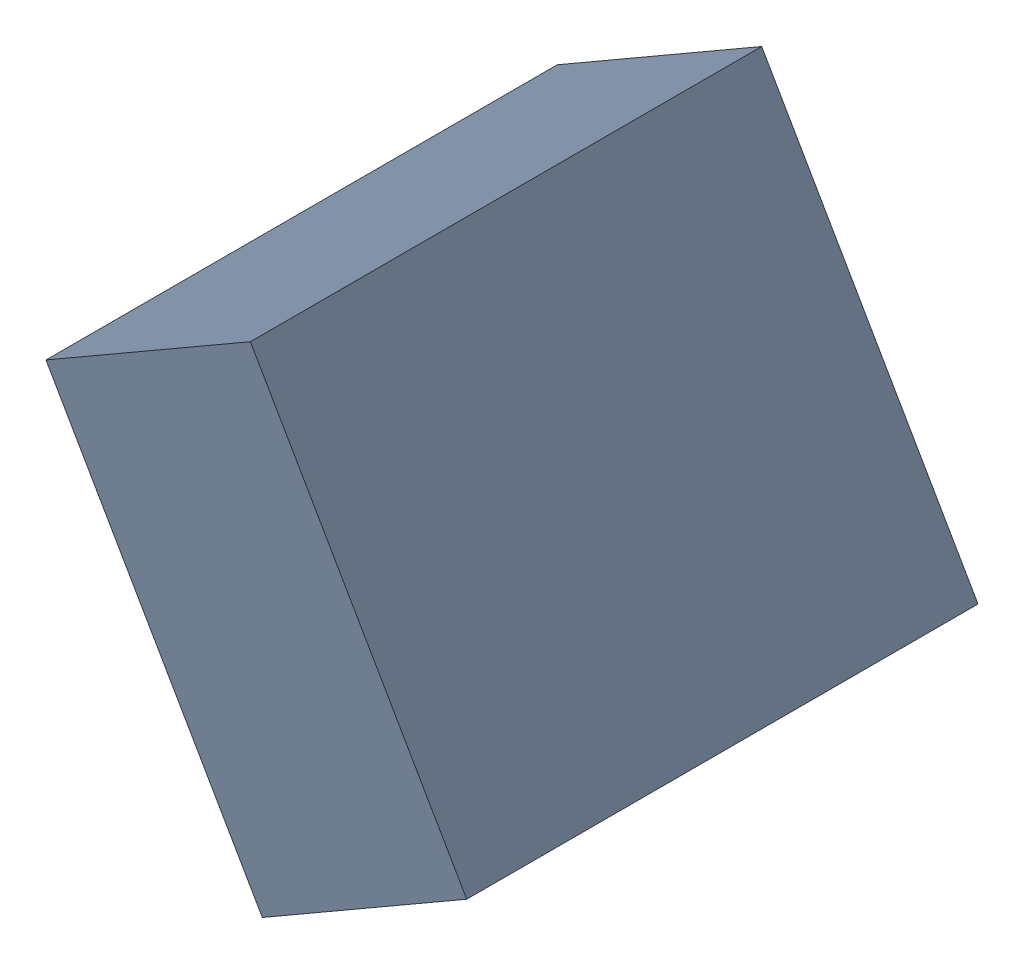
SolidWorks assembly C24_TDA2, configuration Standard. Lengths in mm.
Overall size (1.07 1.25 1.3).
2 component instances, 1 part files, 0 mates.
Components (placement in the parent):
- 885543192-1: 885543192 [Standard] at (36.8927 25.2951 0) size (1.07 1.25 1.3)
  - Extruded_27-1: Extruded_27 [Standard] at origin size (1.07 1.25 1.3)
